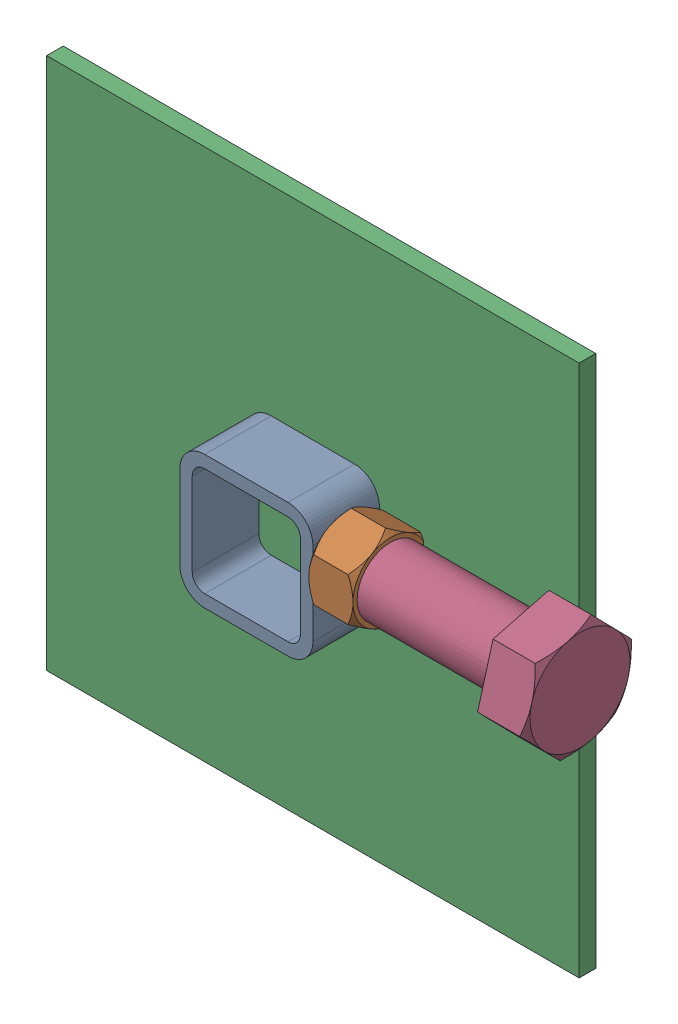
SolidWorks assembly 01-002-00-0(Default)-2, configuration Default. Lengths in mm.
Overall size (216.22 203.2 48.52).
5 component instances, 4 part files, 0 mates.
Components (placement in the parent):
- 01-005-00-0-6-1: 01-005-00-0-6 [Default] at origin size (67.69 50.8 28.57)
  - tube square_ai(PreviewCfg)-1: tube square_ai(PreviewCfg) [Default] at origin size (50.8 50.8 25.4)
  - hex nut_ai(HNUT 0.7500-10-D-C)-1: hex nut_ai(HNUT 0.7500-10-D-C) [Default] at (67.691 31.75 0) x (0 0 -1) z (1 0 0) size (28.57 33 16.89)
- 01-006-00-0-1: 01-006-00-0 [Default] at (-76.2 -76.2 -19.05) x (1 0 0) z (0 -1 0) size (203.2 6.35 203.2)
- hex bolt_ai(PreviewCfg)-1: hex bolt_ai(PreviewCfg) [Default] at (140.0175 31.75 0) x (-1 0 0) z (0 -0.268825 -0.963189) size (93.98 43.99 38.1)
